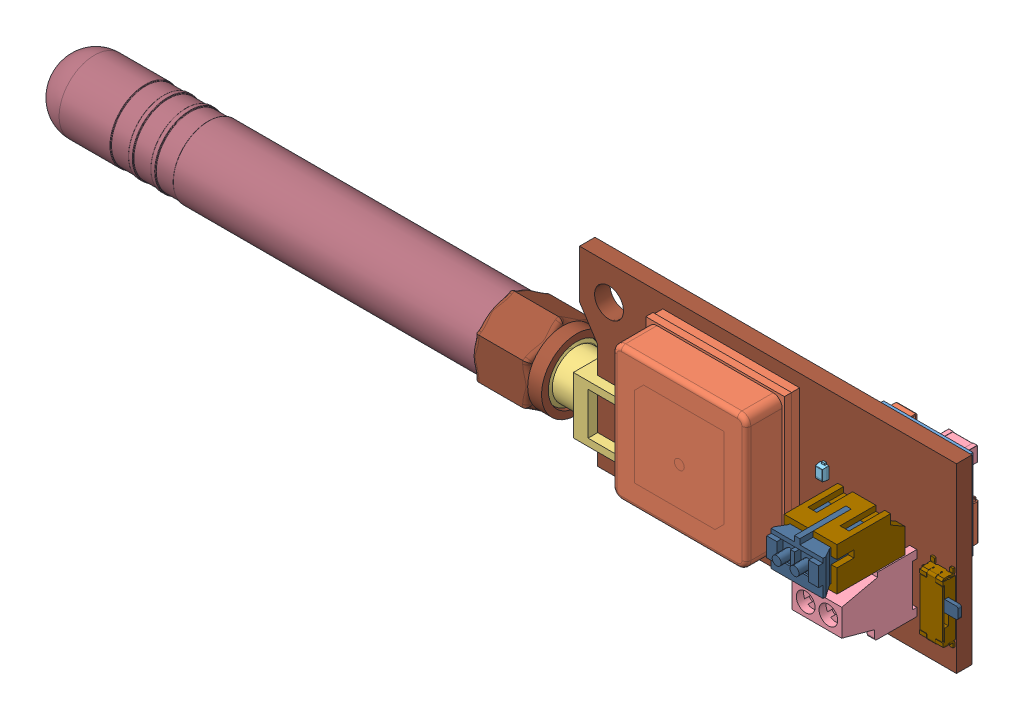
SolidWorks assembly GPS Tracker v15.step, configuration Default. Lengths in mm.
Overall size (103.47 20.32 17.72).
178 component instances, 47 part files, 0 mates.
Components (placement in the parent):
- CYBLE-222014-01 BLE Module_0R0_AP214.step-1: CYBLE-222014-01 BLE Module_0R0_AP214.step [Default] at origin size (10 10 1.79)
  - CYBLE-222005 PCB.step-1: CYBLE-222005 PCB.step [Default] at (28.481 3.6068 0) x (1 0 0) z (0 1 0) size (10 0.5 10)
  - Sheild.step-1: Sheild.step [Default] at (25.7239 -6.0922 -1.49) x (1 0 0) z (0 1 0) size (9.42 1 9.4)
  - 001-96603-A.step-1: 001-96603-A.step [Default] at (33.4749 -3.5332 -0.71) x (0 1 0) z (-1 0 0) size (4.04 0.51 3.87)
  - 2450AT18B100 Antenna 3.2x1.6x0.step-1: 2450AT18B100 Antenna 3.2x1.6x0.step [Default] at (36.0872 2.4305 -1.14) x (1 0 0) z (0 1 0) size (3.2 1.3 1.65)
  - Xtal 1.6x1.0x0.step-1: Xtal 1.6x1.0x0.step [Default] at (36.8746 -2.4839 -0.49) x (1 0 0) z (0 1 0) size (1.6 0.45 1)
  - Xtal 2.5x2.0x0.step-1: Xtal 2.5x2.0x0.step [Default] at (30.2673 -4.1843 -0.495) x (0 1 0) z (-1 0 0) size (2.5 0.51 2)
  - L0603x033(0201).step-1: L0603x033(0201).step [Default] at (30.6421 0.2552 -0.5) x (0 -1 0) z (1 0 0) size (0.6 0.33 0.3)
  - L0603x033(0201).step-2: L0603x033(0201).step [Default] at (30.6471 2.1351 -0.5) x (0 -1 0) z (1 0 0) size (0.6 0.33 0.3)
  - Cap0603x030(0201).step-1: Cap0603x030(0201).step [Default] at (30.3676 1.1604 -0.5) x (1 0 0) z (0 1 0) size (0.6 0.3 0.3)
  - Cap0603x030(0201).step-2: Cap0603x030(0201).step [Default] at (30.3891 -0.6461 -0.5) x (1 0 0) z (0 1 0) size (0.6 0.3 0.3)
  - Cap0603x030(0201).step-3: Cap0603x030(0201).step [Default] at (29.5002 -0.6389 -0.5) x (0 -1 0) z (1 0 0) size (0.6 0.3 0.3)
  - Cap0603x030(0201).step-4: Cap0603x030(0201).step [Default] at (29.5146 -2.1515 -0.5) x (0 -1 0) z (1 0 0) size (0.6 0.3 0.3)
  - Cap0603x030(0201).step-5: Cap0603x030(0201).step [Default] at (30.1454 -2.1371 -0.5) x (0 -1 0) z (1 0 0) size (0.6 0.3 0.3)
  - Cap0603x030(0201).step-6: Cap0603x030(0201).step [Default] at (30.7547 -2.1228 -0.5) x (0 -1 0) z (1 0 0) size (0.6 0.3 0.3)
  - Cap0603x030(0201).step-7: Cap0603x030(0201).step [Default] at (31.9926 -5.9585 -0.5) x (1 0 0) z (0 1 0) size (0.6 0.3 0.3)
  - Cap0603x030(0201).step-8: Cap0603x030(0201).step [Default] at (33.1629 -5.9505 -0.5) x (1 0 0) z (0 1 0) size (0.6 0.3 0.3)
  - Cap0603x030(0201).step-9: Cap0603x030(0201).step [Default] at (34.3088 -5.9554 -0.5) x (1 0 0) z (0 1 0) size (0.6 0.3 0.3)
  - Cap0603x030(0201).step-10: Cap0603x030(0201).step [Default] at (35.4989 -5.9372 -0.5) x (1 0 0) z (0 1 0) size (0.6 0.3 0.3)
  - Cap0603x030(0201).step-11: Cap0603x030(0201).step [Default] at (36.5237 -4.2251 -0.5) x (1 0 0) z (0 1 0) size (0.6 0.3 0.3)
  - Cap0603x030(0201).step-12: Cap0603x030(0201).step [Default] at (36.5155 -3.4775 -0.5) x (1 0 0) z (0 1 0) size (0.6 0.3 0.3)
  - Cap0603x030(0201).step-13: Cap0603x030(0201).step [Default] at (37.4274 -3.7239 -0.5) x (0 -1 0) z (1 0 0) size (0.6 0.3 0.3)
  - Cap0603x030(0201).step-14: Cap0603x030(0201).step [Default] at (36.4416 -5.1698 -0.5) x (0 -1 0) z (1 0 0) size (0.6 0.3 0.3)
  - Cap0603x030(0201).step-15: Cap0603x030(0201).step [Default] at (37.0659 -5.1616 -0.5) x (0 -1 0) z (1 0 0) size (0.6 0.3 0.3)
- CUS-12TB.step-1: CUS-12TB.step [Default] at origin size (5 7.7 1.9)
  - _CUS-12-body.step-1: _CUS-12-body.step [Default] at (37.4289 -10.1846 1.7272) x (0 1 0) z (1 0 0) size (7.7 1.9 3.5)
  - _CUS-12-slider.step-1: _CUS-12-slider.step [Default] at (38.2289 -9.4346 2.9272) x (0 1 0) z (1 0 0) size (1.3 0.4 2.05)
- Antenna.step-1: Antenna.step [Default] at origin size (57.52 9.15 7.94)
  - RSP.step-1: RSP.step [Default] at (-10.2539 -10.8712 -0.3778) x (0 1 0) z (0 0 -1) size (9.15 13.52 7.94)
  - RSP-MA1.step-1: RSP-MA1.step [Default] at (-14.0004 -10.8712 -0.3778) x (0 1 0) z (-1 0 0) size (1.65 1.65 7.62)
  - Antenna_1.step-1: Antenna_1.step [Default] at (-10.2539 -10.8712 -0.3778) x (0 1 0) z (0 0 -1) size (7.9 50 7.9)
- LoRa Module.step-1: LoRa Module.step [Default] at origin size (12.5 14 1.77)
  - PCB.step-1: PCB.step [Default] at (12.3863 -7.4346 0) x (0 -1 0) z (1 0 0) size (11.6 0.6 12.5)
  - Shield.step-1: Shield.step [Default] at (12.3863 -7.4346 -1.76) x (0 -1 0) z (1 0 0) size (11.42 1.16 12.42)
  - Label.step-1: Label.step [Default] at (12.3863 -7.4346 -1.76) x (0 0 -1) z (1 0 0) size (0.01 14 9.3)
- R0402.step-1: R0402.step [Default] at (13.7605 8.0124 0) x (0 -1 0) z (0 0 1) size (1.1 0.5 0.32)
  - R0402_detailed.step-1: R0402_detailed.step [Default] at (7.3529 -0.5851 0) x (-1 0 0) z (0 0 -1) size (1.1 0.5 0.32)
    - Part 6.step-1: Part 6.step [Default] at origin size (0.74 0.5 0.02)
    - Part 5.step-1: Part 5.step [Default] at origin size (1.05 0.5 0.27)
    - Part 4.step-1: Part 4.step [Default] at origin size (0.08 0.38 0.03)
    - Part 3.step-1: Part 3.step [Default] at origin size (0.08 0.38 0.03)
    - Part 2.step-1: Part 2.step [Default] at origin size (0.25 0.5 0.32)
    - Part 1.step-1: Part 1.step [Default] at origin size (0.25 0.5 0.32)
- R0402_1.step-1: R0402_1.step [Default] at (13.7605 8.0124 0) x (0 -1 0) z (0 0 1) size (1.1 0.5 0.32)
  - R0402_detailed_1.step-1: R0402_detailed_1.step [Default] at (13.1501 7.891 0) x (-1 0 0) z (0 0 -1) size (1.1 0.5 0.32)
    - Part 6.step-1: Part 6.step [Default] at origin size (0.74 0.5 0.02)
    - Part 5.step-1: Part 5.step [Default] at origin size (1.05 0.5 0.27)
    - Part 4.step-1: Part 4.step [Default] at origin size (0.08 0.38 0.03)
    - Part 3.step-1: Part 3.step [Default] at origin size (0.08 0.38 0.03)
    - Part 2.step-1: Part 2.step [Default] at origin size (0.25 0.5 0.32)
    - Part 1.step-1: Part 1.step [Default] at origin size (0.25 0.5 0.32)
- R0402_2.step-1: R0402_2.step [Default] at (20.3826 -3.2472 0) x (0 -1 0) z (0 0 -1) size (1.1 0.5 0.32)
  - R0402_detailed_2.step-1: R0402_detailed_2.step [Default] at origin size (1.1 0.5 0.32)
    - Part 6.step-1: Part 6.step [Default] at origin size (0.74 0.5 0.02)
    - Part 5.step-1: Part 5.step [Default] at origin size (1.05 0.5 0.27)
    - Part 4.step-1: Part 4.step [Default] at origin size (0.08 0.38 0.03)
    - Part 3.step-1: Part 3.step [Default] at origin size (0.08 0.38 0.03)
    - Part 2.step-1: Part 2.step [Default] at origin size (0.25 0.5 0.32)
    - Part 1.step-1: Part 1.step [Default] at origin size (0.25 0.5 0.32)
- R0402_3.step-1: R0402_3.step [Default] at (27.402 -5.6852 0) x (0 -1 0) z (0 0 -1) size (1.1 0.5 0.32)
  - R0402_detailed_3.step-1: R0402_detailed_3.step [Default] at origin size (1.1 0.5 0.32)
    - Part 6.step-1: Part 6.step [Default] at origin size (0.74 0.5 0.02)
    - Part 5.step-1: Part 5.step [Default] at origin size (1.05 0.5 0.27)
    - Part 4.step-1: Part 4.step [Default] at origin size (0.08 0.38 0.03)
    - Part 3.step-1: Part 3.step [Default] at origin size (0.08 0.38 0.03)
    - Part 2.step-1: Part 2.step [Default] at origin size (0.25 0.5 0.32)
    - Part 1.step-1: Part 1.step [Default] at origin size (0.25 0.5 0.32)
- R0402_4.step-1: R0402_4.step [Default] at (13.7605 8.0124 0) x (0 -1 0) z (0 0 -1) size (0.5 1.1 0.32)
  - R0402_detailed_4.step-1: R0402_detailed_4.step [Default] at (4.9505 -10.644 0) x (0 1 0) z (0 0 1) size (1.1 0.5 0.32)
    - Part 6.step-1: Part 6.step [Default] at origin size (0.74 0.5 0.02)
    - Part 5.step-1: Part 5.step [Default] at origin size (1.05 0.5 0.27)
    - Part 4.step-1: Part 4.step [Default] at origin size (0.08 0.38 0.03)
    - Part 3.step-1: Part 3.step [Default] at origin size (0.08 0.38 0.03)
    - Part 2.step-1: Part 2.step [Default] at origin size (0.25 0.5 0.32)
    - Part 1.step-1: Part 1.step [Default] at origin size (0.25 0.5 0.32)
- R0402_5.step-1: R0402_5.step [Default] at (19.1771 -2.1738 0) x (0 -1 0) z (0 0 1) size (1.1 0.5 0.32)
  - R0402_detailed_5.step-1: R0402_detailed_5.step [Default] at (13.1345 -7.8704 0) x (-1 0 0) z (0 0 -1) size (1.1 0.5 0.32)
    - Part 6.step-1: Part 6.step [Default] at origin size (0.74 0.5 0.02)
    - Part 5.step-1: Part 5.step [Default] at origin size (1.05 0.5 0.27)
    - Part 4.step-1: Part 4.step [Default] at origin size (0.08 0.38 0.03)
    - Part 3.step-1: Part 3.step [Default] at origin size (0.08 0.38 0.03)
    - Part 2.step-1: Part 2.step [Default] at origin size (0.25 0.5 0.32)
    - Part 1.step-1: Part 1.step [Default] at origin size (0.25 0.5 0.32)
- R0402_6.step-1: R0402_6.step [Default] at (2.0397 21.115 0) x (0 -1 0) z (0 0 1) size (0.5 1.1 0.32)
  - R0402_detailed_6.step-1: R0402_detailed_6.step [Default] at (36.368 12.1316 0) x (0 1 0) z (0 0 -1) size (1.1 0.5 0.32)
    - Part 6.step-1: Part 6.step [Default] at origin size (0.74 0.5 0.02)
    - Part 5.step-1: Part 5.step [Default] at origin size (1.05 0.5 0.27)
    - Part 4.step-1: Part 4.step [Default] at origin size (0.08 0.38 0.03)
    - Part 3.step-1: Part 3.step [Default] at origin size (0.08 0.38 0.03)
    - Part 2.step-1: Part 2.step [Default] at origin size (0.25 0.5 0.32)
    - Part 1.step-1: Part 1.step [Default] at origin size (0.25 0.5 0.32)
- R0402_7.step-1: R0402_7.step [Default] at (2.0397 21.115 0) x (0 -1 0) z (0 0 1) size (1.1 0.5 0.32)
  - R0402_detailed_7.step-1: R0402_detailed_7.step [Default] at (36.4067 10.326 0) x (-1 0 0) z (0 0 -1) size (1.1 0.5 0.32)
    - Part 6.step-1: Part 6.step [Default] at origin size (0.74 0.5 0.02)
    - Part 5.step-1: Part 5.step [Default] at origin size (1.05 0.5 0.27)
    - Part 4.step-1: Part 4.step [Default] at origin size (0.08 0.38 0.03)
    - Part 3.step-1: Part 3.step [Default] at origin size (0.08 0.38 0.03)
    - Part 2.step-1: Part 2.step [Default] at origin size (0.25 0.5 0.32)
    - Part 1.step-1: Part 1.step [Default] at origin size (0.25 0.5 0.32)
- R0201.step-1: R0201.step [Default] at (10.521 -19.9765 0) size (0.6 0.3 0.23)
  - R0201_detailed.step-1: R0201_detailed.step [Default] at (2.451 4.5887 1.7272) size (0.6 0.3 0.23)
    - Part 6_1.step-1: Part 6_1.step [Default] at origin size (0.34 0.3 0.02)
    - Part 5_1.step-1: Part 5_1.step [Default] at origin size (0.55 0.3 0.18)
    - Part 4_1.step-1: Part 4_1.step [Default] at origin size (0.03 0.2 0.03)
    - Part 3_1.step-1: Part 3_1.step [Default] at origin size (0.03 0.2 0.03)
    - Part 2_1.step-1: Part 2_1.step [Default] at origin size (0.15 0.3 0.23)
    - Part 1_1.step-1: Part 1_1.step [Default] at origin size (0.15 0.3 0.23)
- R0201_1.step-1: R0201_1.step [Default] at (10.521 -19.9765 0) size (0.3 0.6 0.23)
  - R0201_detailed_1.step-1: R0201_detailed_1.step [Default] at (-6.6471 16.1051 1.7272) x (0 -1 0) z (0 0 1) size (0.6 0.3 0.23)
    - Part 6_1.step-1: Part 6_1.step [Default] at origin size (0.34 0.3 0.02)
    - Part 5_1.step-1: Part 5_1.step [Default] at origin size (0.55 0.3 0.18)
    - Part 4_1.step-1: Part 4_1.step [Default] at origin size (0.03 0.2 0.03)
    - Part 3_1.step-1: Part 3_1.step [Default] at origin size (0.03 0.2 0.03)
    - Part 2_1.step-1: Part 2_1.step [Default] at origin size (0.15 0.3 0.23)
    - Part 1_1.step-1: Part 1_1.step [Default] at origin size (0.15 0.3 0.23)
- R0201_2.step-1: R0201_2.step [Default] at (10.521 -19.9765 0) size (0.6 0.3 0.23)
  - R0201_detailed_2.step-1: R0201_detailed_2.step [Default] at (4.7243 4.6218 1.7272) size (0.6 0.3 0.23)
    - Part 6_1.step-1: Part 6_1.step [Default] at origin size (0.34 0.3 0.02)
    - Part 5_1.step-1: Part 5_1.step [Default] at origin size (0.55 0.3 0.18)
    - Part 4_1.step-1: Part 4_1.step [Default] at origin size (0.03 0.2 0.03)
    - Part 3_1.step-1: Part 3_1.step [Default] at origin size (0.03 0.2 0.03)
    - Part 2_1.step-1: Part 2_1.step [Default] at origin size (0.15 0.3 0.23)
    - Part 1_1.step-1: Part 1_1.step [Default] at origin size (0.15 0.3 0.23)
- R0201_3.step-1: R0201_3.step [Default] at (10.521 -19.9765 0) size (0.6 0.3 0.23)
  - R0201_detailed_3.step-1: R0201_detailed_3.step [Default] at (8.8191 4.6452 2.1631) size (0.6 0.3 0.23)
    - Part 6_1.step-1: Part 6_1.step [Default] at origin size (0.34 0.3 0.02)
    - Part 5_1.step-1: Part 5_1.step [Default] at origin size (0.55 0.3 0.18)
    - Part 4_1.step-1: Part 4_1.step [Default] at origin size (0.03 0.2 0.03)
    - Part 3_1.step-1: Part 3_1.step [Default] at origin size (0.03 0.2 0.03)
    - Part 2_1.step-1: Part 2_1.step [Default] at origin size (0.15 0.3 0.23)
    - Part 1_1.step-1: Part 1_1.step [Default] at origin size (0.15 0.3 0.23)
- C0402_035.step-1: C0402_035.step [Default] at (20.9649 -18.2521 -2.6622) x (0 -1 0) z (0 0 1) size (1 0.5 0.35)
  - C0402_035_1.step-1: C0402_035_1.step [Default] at (-10.5375 -0.7734 2.3137) size (1 0.5 0.35)
    - Part 3_2.step-1: Part 3_2.step [Default] at origin size (0.85 0.49 0.35)
    - Part 2_2.step-1: Part 2_2.step [Default] at origin size (0.15 0.5 0.35)
    - Part 1_2.step-1: Part 1_2.step [Default] at origin size (0.15 0.5 0.35)
- C0402_035_2.step-1: C0402_035_2.step [Default] at (22.9247 6.0446 -2.6622) x (0 -1 0) z (0 0 1) size (0.5 1 0.35)
  - C0402_035_3.step-1: C0402_035_3.step [Default] at (3.9591 1.9269 2.3137) x (0 -1 0) z (0 0 1) size (1 0.5 0.35)
    - Part 3_2.step-1: Part 3_2.step [Default] at origin size (0.85 0.49 0.35)
    - Part 2_2.step-1: Part 2_2.step [Default] at origin size (0.15 0.5 0.35)
    - Part 1_2.step-1: Part 1_2.step [Default] at origin size (0.15 0.5 0.35)
- C0805_085.step-1: C0805_085.step [Default] at origin size (2 1.25 0.85)
  - C0805_085_1.step-1: C0805_085_1.step [Default] at (24.8156 -7.8144 0.015) x (1 0 0) z (0 0 -1) size (2 1.25 0.85)
    - Part 3_3.step-1: Part 3_3.step [Default] at origin size (1.8 1.22 0.82)
    - Part 2_3.step-1: Part 2_3.step [Default] at origin size (0.2 1.25 0.85)
    - Part 1_3.step-1: Part 1_3.step [Default] at origin size (0.2 1.25 0.85)
- C0603_060.step-1: C0603_060.step [Default] at origin size (1.6 0.8 0.6)
  - C0603_060_1.step-1: C0603_060_1.step [Default] at (16.2684 1.683 -0.585) size (1.6 0.8 0.6)
    - Part 3_4.step-1: Part 3_4.step [Default] at origin size (1.4 0.77 0.57)
    - Part 2_4.step-1: Part 2_4.step [Default] at origin size (0.2 0.8 0.6)
    - Part 1_4.step-1: Part 1_4.step [Default] at origin size (0.2 0.8 0.6)
- C0603_060_2.step-1: C0603_060_2.step [Default] at (14.955 6.5211 0) size (0.8 1.6 0.6)
  - C0603_060_3.step-1: C0603_060_3.step [Default] at (6.6336 -14.5529 -0.585) x (0 1 0) z (0 0 1) size (1.6 0.8 0.6)
    - Part 3_4.step-1: Part 3_4.step [Default] at origin size (1.4 0.77 0.57)
    - Part 2_4.step-1: Part 2_4.step [Default] at origin size (0.2 0.8 0.6)
    - Part 1_4.step-1: Part 1_4.step [Default] at origin size (0.2 0.8 0.6)
- C0603_060_4.step-1: C0603_060_4.step [Default] at (20.7805 6.2602 0) size (0.8 1.6 0.6)
  - C0603_060_5.step-1: C0603_060_5.step [Default] at (1.3279 -7.2606 -0.585) x (0 1 0) z (0 0 1) size (1.6 0.8 0.6)
    - Part 3_4.step-1: Part 3_4.step [Default] at origin size (1.4 0.77 0.57)
    - Part 2_4.step-1: Part 2_4.step [Default] at origin size (0.2 0.8 0.6)
    - Part 1_4.step-1: Part 1_4.step [Default] at origin size (0.2 0.8 0.6)
- C0603_060_6.step-1: C0603_060_6.step [Default] at (22.6933 5.6516 0) size (1.6 0.8 0.6)
  - C0603_060_7.step-1: C0603_060_7.step [Default] at (2.6007 -7.3901 -0.585) size (1.6 0.8 0.6)
    - Part 3_4.step-1: Part 3_4.step [Default] at origin size (1.4 0.77 0.57)
    - Part 2_4.step-1: Part 2_4.step [Default] at origin size (0.2 0.8 0.6)
    - Part 1_4.step-1: Part 1_4.step [Default] at origin size (0.2 0.8 0.6)
- SAM-MQ8-0-10.step-1: SAM-MQ8-0-10.step [Default] at (21.3152 -12.9078 1.7272) x (0 1 0) z (0 0 1) size (15.5 15.5 5.8)
- SAMTEC_SMA-J-P-H-ST-EM1.step-1: SAMTEC_SMA-J-P-H-ST-EM1.step [Default] at (-1.27 -10.8712 0.3972) x (0 1 0) z (-1 0 0) size (6.35 6.35 13.33)
- Wire Terminal 2 Pin.step-1: Wire Terminal 2 Pin.step [Default] at (31.6601 -6.708 4.7272) x (-1 0 0) z (0 1 0) size (5.54 11.8 6.5)
- SOD-523.step-1: SOD-523.step [Default] at (24.148 -4.1736 1.7272) x (0.000005 1 0) z (0 0 1) size (1.7 0.9 0.7)
- SOD-523.step-2: SOD-523.step [Default] at (26.9756 -7.6478 1.7272) x (0 -1 0) z (0 0 1) size (1.7 0.9 0.7)
- SOT23-5.step-1: SOT23-5.step [Default] at (24.6866 -4.1964 0.0078) x (1 0 0) z (0 0 -1) size (2.84 3.01 1.19)
- SOT-666.step-1: SOT-666.step [Default] at (25.0636 0.4873 0) x (0 -1 0) z (0 0 -1) size (1.59 1.6 0.6)
- 0603.step-1: 0603.step [Default] at (25.4805 -7.5846 1.8523) x (0.000073 1 0) z (1 -0.000073 0) size (1.61 0.75 0.8)
- 0603.step-2: 0603.step [Default] at (6.4404 -14.9151 1.8523) x (0 -1 0) z (-1 0 0) size (1.61 0.75 0.8)
- User Library-S2B.step-1: User Library-S2B.step [Default] at (39.1401 -0.6588 1.6272) size (5.9 8.2 7.6)
- User Library-PHR-2 v2.step-1: User Library-PHR-2 v2.step [Default] at (29.1401 -6.9338 9.1522) x (-1 0 0) z (0 0 -1) size (5.8 4.5 7.64)
- GPS Tracker.step-1: GPS Tracker.step [Default] at origin size (42.16 20.32 1.73)
